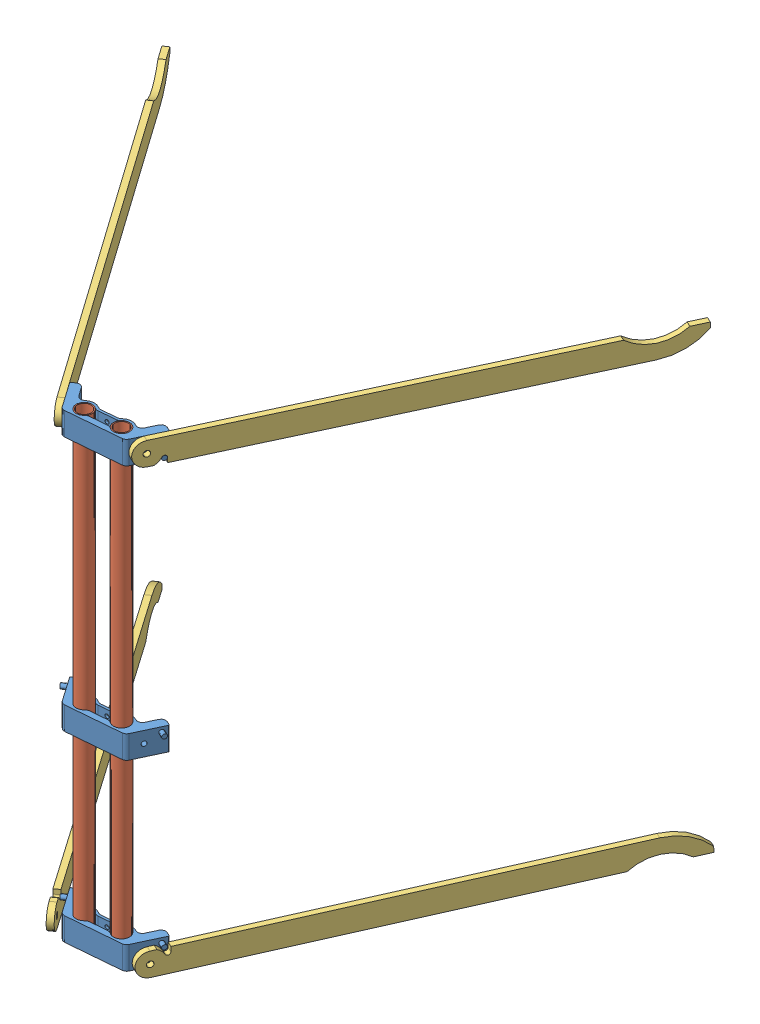
SolidWorks assembly stand_4k, configuration По умолчанию. Lengths in mm.
Overall size (448.08 409.2 352.71).
9 component instances, 3 part files, 19 mates.
Components (placement in the parent):
- stand_head-1: stand_head [По умолчанию] at (-124.9975 137.7951 -67.4924) x (0.996314 0 -0.085782) z (0.085782 0 0.996314) size (85.66 20 27.54)
- stand_head-2: stand_head [По умолчанию] at (-45.2924 537.7951 -74.355) x (-0.996314 0 0.085782) z (0.085782 0 0.996314) size (85.66 20 27.54)
- stand_head-3: stand_head [По умолчанию] at (-124.9975 296.3927 -67.4924) x (0.996314 0 -0.085782) z (0.085782 0 0.996314) size (85.66 20 27.54)
- Pipe_14mm_500-3: Pipe_14mm_500 [500mm] at (-68.8277 137.7951 -56.2694) size (14 400 14)
- Pipe_14mm_500-4: Pipe_14mm_500 [500mm] at (-98.7172 137.7951 -53.696) size (14 400 14)
- stand_horizont_leg-1: stand_horizont_leg [По умолчанию] at (-109.6742 537.5806 -45.5441) x (-0.819942 0 0.572447) z (-0.012152 -0.999775 -0.017405) size (5 378 20)
- stand_horizont_leg-2: stand_horizont_leg [По умолчанию] at (-52.0256 537.784 -48.1713) x (-0.905724 0 -0.423867) z (0.000473 -0.999999 -0.001011) size (5 378 20)
- stand_horizont_leg-3: stand_horizont_leg [По умолчанию] at (-117.9723 137.8329 -39.961) x (0.819942 0 -0.572447) z (-0.002158 0.999993 -0.003091) size (5 378 20)
- stand_horizont_leg-4: stand_horizont_leg [По умолчанию] at (-51.0515 137.6471 -47.8935) x (0.905724 0 0.423867) z (-0.00632 0.999889 0.013505) size (5 378 20)
Mates (geometry in assembly coordinates):
- Концентричный3: concentric anti-aligned: cylinder of stand_head-1 through (-98.7172 137.7951 -53.696) axis (0 1 0) radius 7; cylinder of Pipe_14mm_500-4 through (-98.7172 537.7951 -53.696) axis (0 -1 0) radius 7
- Совпадение1: coincident aligned: plane of stand_head-1 through (-68.8277 137.7951 -56.2694) normal (0 -1 0); plane of Pipe_14mm_500-4 through (-98.7172 137.7951 -53.696) normal (0 -1 0)
- Концентричный4: concentric anti-aligned: cylinder of stand_head-1 through (-68.8277 137.7951 -56.2694) axis (0 1 0) radius 7; cylinder of Pipe_14mm_500-3 through (-68.8277 537.7951 -56.2694) axis (0 -1 0) radius 7
- Совпадение2: coincident aligned: plane of stand_head-1 through (-68.8277 137.7951 -56.2694) normal (0 -1 0); plane of Pipe_14mm_500-3 through (-68.8277 137.7951 -56.2694) normal (0 -1 0)
- Концентричный5: concentric aligned: cylinder of Pipe_14mm_500-4 through (-98.7172 537.7951 -53.696) axis (0 -1 0) radius 7; cylinder of stand_head-2 through (-98.7172 537.7951 -53.696) axis (0 -1 0) radius 7
- Совпадение3: coincident aligned: plane of stand_head-2 through (-98.7172 537.7951 -53.696) normal (0 1 0); plane of Pipe_14mm_500-4 through (-98.7172 537.7951 -53.696) normal (0 1 0)
- Совпадение4: coincident aligned: plane of stand_head-1 through (-108.4724 157.7951 -43.8227) normal (0.085782 0 0.996314); plane of stand_head-2 through (-57.5284 517.7951 -48.209) normal (0.085782 0 0.996314)
- Концентричный6: concentric anti-aligned: cylinder of Pipe_14mm_500-3 through (-68.8277 537.7951 -56.2694) axis (0 -1 0) radius 7; cylinder of stand_head-3 through (-68.8277 296.3927 -56.2694) axis (0 1 0) radius 7
- Параллельность1: parallel aligned: plane of stand_head-2 through (-57.5284 517.7951 -48.209) normal (0.085782 0 0.996314); plane of stand_head-3 through (-108.4724 316.3927 -43.8227) normal (0.085782 0 0.996314)
- Концентричный7: concentric anti-aligned: cylinder of stand_head-2 through (-111.4192 527.7951 -56.778) axis (-0.819942 0 0.572447) radius 2; cylinder of stand_horizont_leg-1 through (-119.6186 527.7951 -51.0535) axis (0.819942 0 -0.572447) radius 2.5
- Концентричный8: concentric aligned: cylinder of stand_head-2 through (-56.8395 527.7951 -61.4773) axis (0.905724 0 0.423867) radius 2; cylinder of stand_horizont_leg-2 through (-52.3109 527.7951 -59.3579) axis (0.905724 0 0.423867) radius 2.5
- Совпадение10: coincident anti-aligned: plane of stand_head-2 through (-45.2924 517.7951 -74.355) normal (0.905724 0 0.423867); plane of stand_horizont_leg-2 through (103.6674 538.2058 -392.6542) normal (-0.905724 0 -0.423867)
- Концентричный10: concentric: cylinder of stand_horizont_leg-3 through (-119.6186 147.7951 -51.0535) axis (-0.819942 0 0.572447) radius 2.5; cylinder of stand_head-1 through (-111.4192 147.7951 -56.778) axis (-0.819942 0 0.572447) radius 2
- Расстояние1: distance = 6 mm anti-aligned: plane of stand_head-1 through (-57.5284 157.7951 -48.209) normal (0.905724 0 0.423867); plane of stand_horizont_leg-4 through (109.1525 143.2832 -390.2193) normal (-0.905724 0 -0.423867)
- Совпадение16: coincident anti-aligned: plane of stand_head-2 through (-108.4724 517.7951 -43.8227) normal (-0.819942 0 0.572447); plane of stand_horizont_leg-1 through (-326.0103 545.6046 -355.4123) normal (0.819942 0 -0.572447)
- Концентричный9: concentric anti-aligned: cylinder of stand_head-1 through (-56.8395 147.7951 -61.4773) axis (0.905724 0 0.423867) radius 2; cylinder of stand_horizont_leg-4 through (-42.3479 147.7951 -54.6954) axis (-0.905724 0 -0.423867) radius 2.5
- Расстояние3: distance = 5 mm: plane of stand_horizont_leg-3 through (-330.2559 136.4077 -352.7591) normal (0.819942 0 -0.572447); plane of stand_head-1 through (-124.9975 157.7951 -67.4924) normal (-0.819942 0 0.572447)
- Совпадение20: coincident aligned: plane of stand_head-2 through (-98.7659 537.7951 -54.3437) normal (0 1 0); plane of stand_horizont_leg-2
- Касательность1: tangent aligned: cylinder of stand_head-1 through (-126.235 153.7951 -60.5305) axis (0.819942 0 -0.572447) radius 2; cylinder of stand_horizont_leg-3 through (-130.3487 153.7515 -57.6883) axis (0.819942 0 -0.572447) radius 2.05
